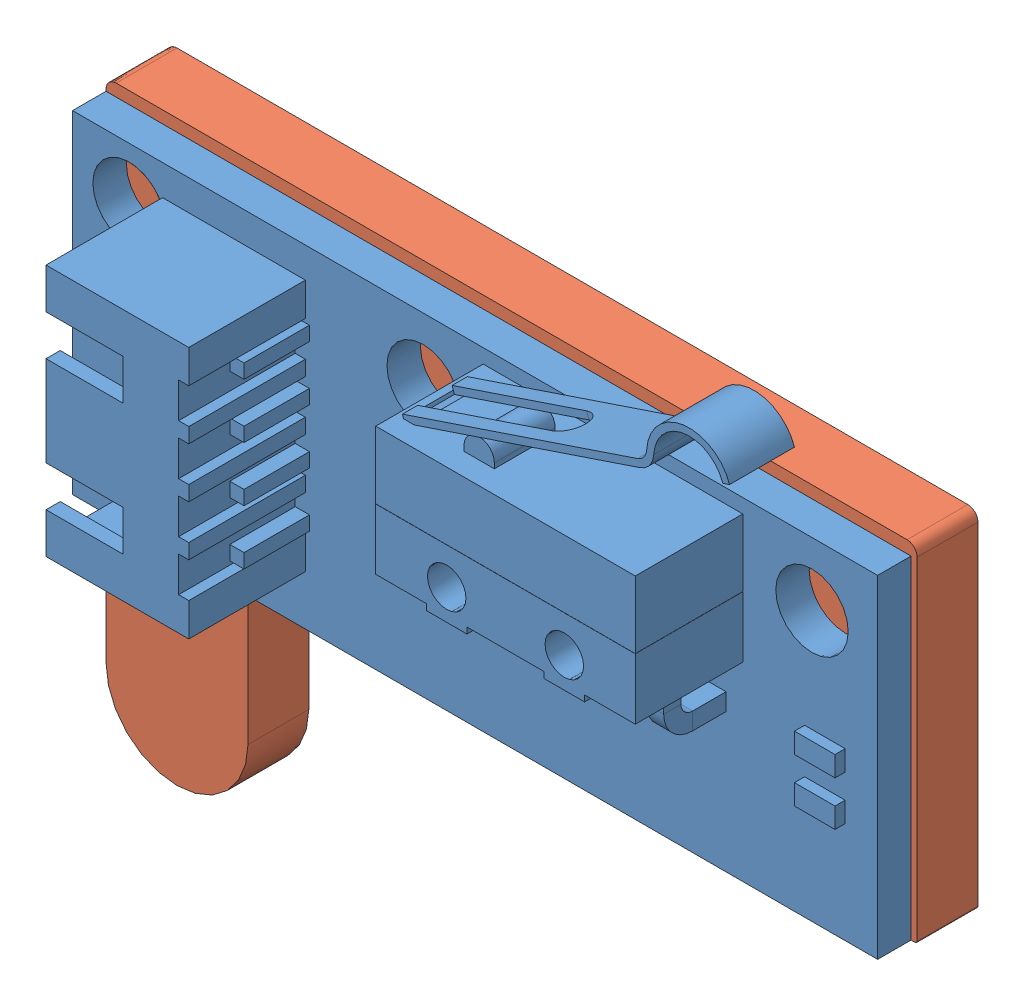
SolidWorks assembly LIMIT SWITCH OFFICIAL, configuration Default. Lengths in mm.
Overall size (40 33.86 10.4).
2 component instances, 2 part files, 4 mates.
Components (placement in the parent):
- Switch-1: Switch [Default] at (19.85 16.2 1.5) x (1 0 0) z (0 -1 0) size (39.7 9.4 22.36)
- LIMIT SWITCH HOLDER-1: LIMIT SWITCH HOLDER [Default] at origin size (40 28.5 3)
Mates (geometry in assembly coordinates):
- Coincident1: coordinate: point of LIMIT SWITCH HOLDER-1
- Coincident2: coincident anti-aligned: plane of Switch-1 through (19.85 16.2 1.5) normal (0 0 -1); plane of LIMIT SWITCH HOLDER-1 through (3.5 0 1.5) normal (0 0 1)
- Coincident3: coincident aligned: plane of Switch-1 through (0 8 3.15) normal (-1 0 0); plane of LIMIT SWITCH HOLDER-1 through (0 0 1.5) normal (-1 0 0)
- Coincident4: coincident aligned: plane of LIMIT SWITCH HOLDER-1 through (39.9 8 1.5) normal (0 -1 0); plane of Switch-1 through (0 8 3.15) normal (0 -1 0)
